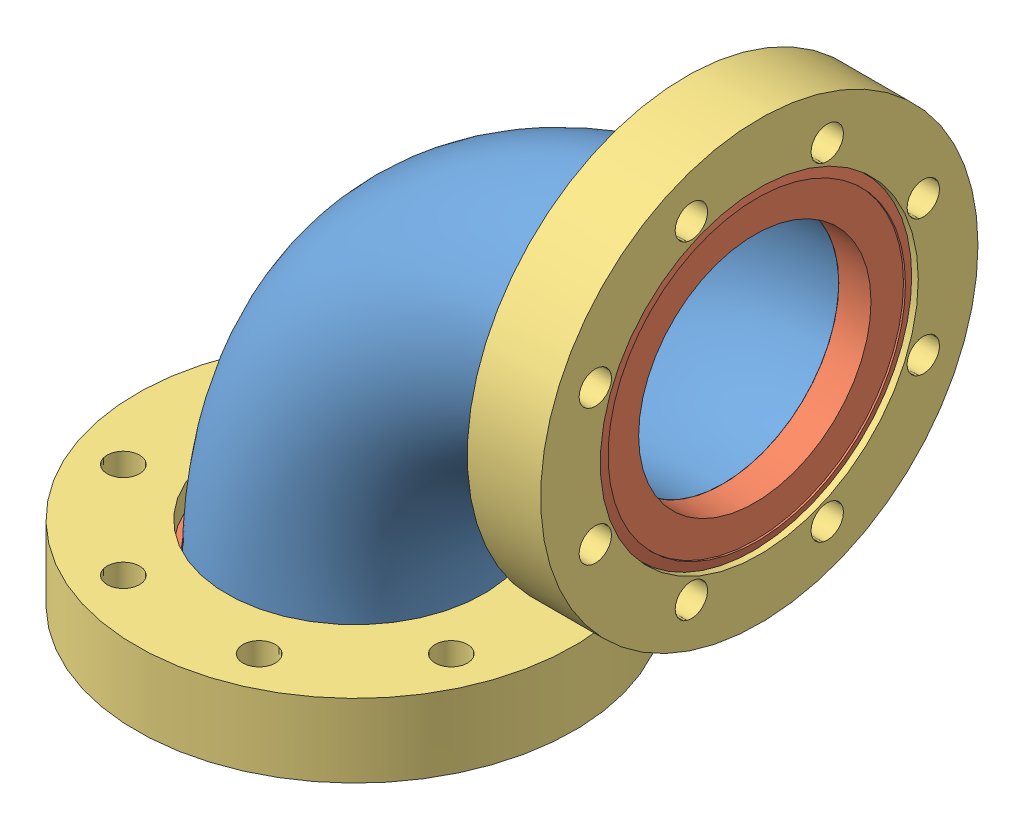
SolidWorks assembly L4-403004_1, configuration Default. Lengths in mm.
Overall size (161.67 161.67 113.54).
7 component instances, 3 part files, 0 mates.
Components (placement in the parent):
- 403004-001_1-1: 403004-001_1 [Default] at origin size (128.92 128.92 67.08)
- 100021 (4.5 X 2.5 R)_2-1: 100021 (4.5 X 2.5 R)_2 [Default] at (92.202 95.377 0) x (1 0 0) z (0 0 -1) size (19.05 113.54 113.54)
  - 100021 (4.5 X 2.5 INS)_2-1: 100021 (4.5 X 2.5 INS)_2 [Default] at origin size (12.04 82.3 82.3)
  - 100021 (4.5 X 2.5 REC)_2-1: 100021 (4.5 X 2.5 REC)_2 [Default] at (-6.35 0 0) x (1 0 0) z (0 0 -1) size (19.05 113.54 113.54)
- 100021 (4.5 X 2.5 R)_2-2: 100021 (4.5 X 2.5 R)_2 [Default] at (0 3.175 0) x (0 -1 0) z (0 0 -1) size (19.05 113.54 113.54)
  - 100021 (4.5 X 2.5 INS)_2-1: 100021 (4.5 X 2.5 INS)_2 [Default] at origin size (12.04 82.3 82.3)
  - 100021 (4.5 X 2.5 REC)_2-1: 100021 (4.5 X 2.5 REC)_2 [Default] at (-6.35 0 0) x (1 0 0) z (0 0 -1) size (19.05 113.54 113.54)
